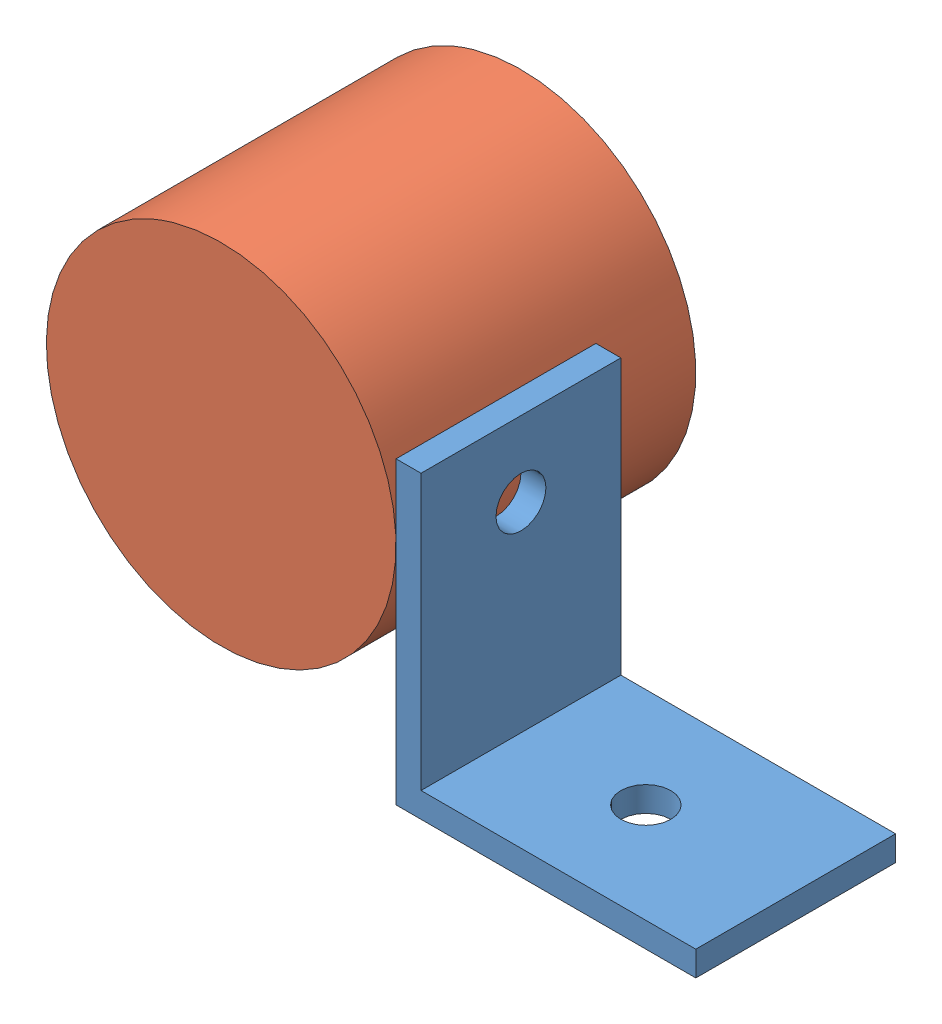
SolidWorks assembly ConstantForceSpringAssembly, configuration Default. Lengths in mm.
Overall size (88.67 56.92 38.1).
2 component instances, 2 part files, 3 mates.
Components (placement in the parent):
- ConstantForceSpringBracket-1: ConstantForceSpringBracket [Default] at (-16.6671 2.4853 21.6694) size (38.1 38.1 25.4)
- ConstantForceSpring-1: ConstantForceSpring [Default] at (-38.8921 31.0603 8.9694) x (-0.332462 0.943117 0) z (0 0 1) size (44.45 44.45 38.1)
Mates (geometry in assembly coordinates):
- Tangent1: tangent anti-aligned: plane of ConstantForceSpringBracket-1 through (-16.6671 2.4853 47.0694) normal (-1 0 0); cylinder of ConstantForceSpring-1 through (-38.8921 31.0603 47.0694) axis (0 0 -1) radius 22.225
- Coincident1: coincident aligned: plane of ConstantForceSpringBracket-1 through (-16.6671 2.4853 47.0694) normal (0 0 1); circle of ConstantForceSpring-1
- Coincident3: coincident: point of ConstantForceSpringBracket-1; cylinder of ConstantForceSpring-1 through (-38.8921 31.0603 47.0694) axis (0 0 -1) radius 22.225
